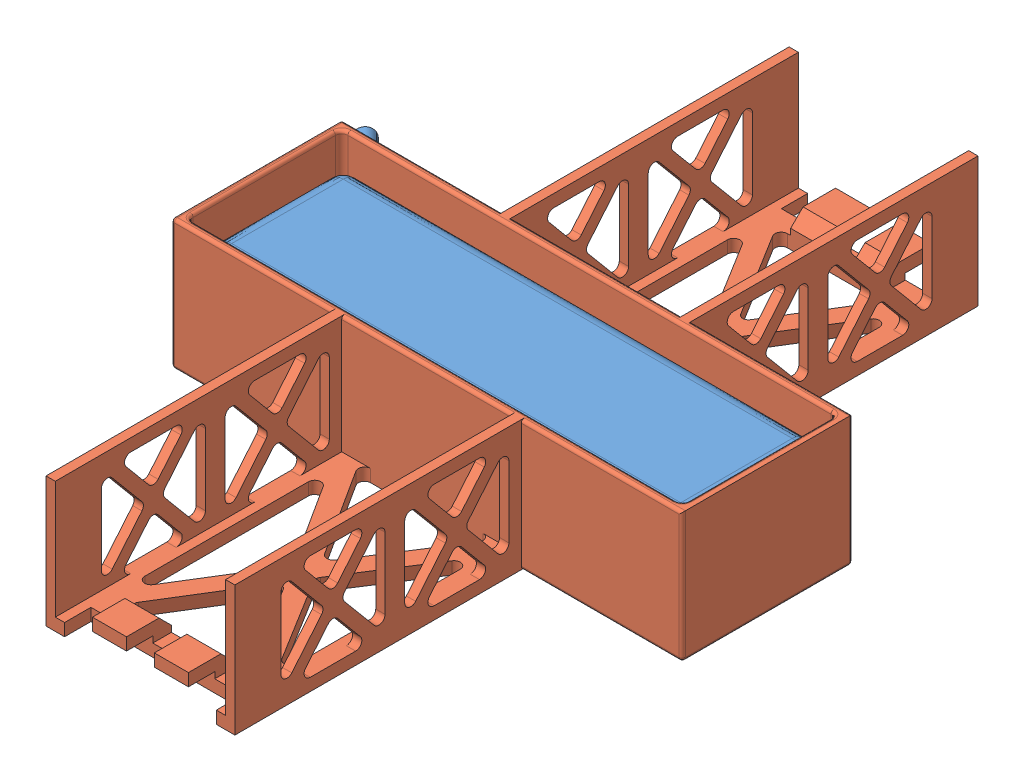
SolidWorks assembly Battery Mount Assem, configuration Default. Lengths in mm.
Overall size (174.8 42 240).
2 component instances, 2 part files, 4 mates.
Components (placement in the parent):
- 5100mAh 3S Battery-1: 5100mAh 3S Battery [Default] at origin size (169.8 31 67.87)
- Battery Mount-1: Battery Mount [Hard Shell Battery Compatible] at (0 -15.5 0) size (165 42 240)
Mates (geometry in assembly coordinates):
- Coincident1: coordinate: point of 5100mAh 3S Battery-1
- Coincident2: coincident anti-aligned: plane of 5100mAh 3S Battery-1 through (0 -15.5 0) normal (0 -1 0); plane of Battery Mount-1 through (0 -15.5 0) normal (0 1 0)
- Coincident3: coincident aligned: plane of Battery Mount-1 through (0 -15.5 0) normal (0 0 1)
- Coincident4: coincident aligned: plane of Battery Mount-1 through (0 -15.5 0) normal (1 0 0)
